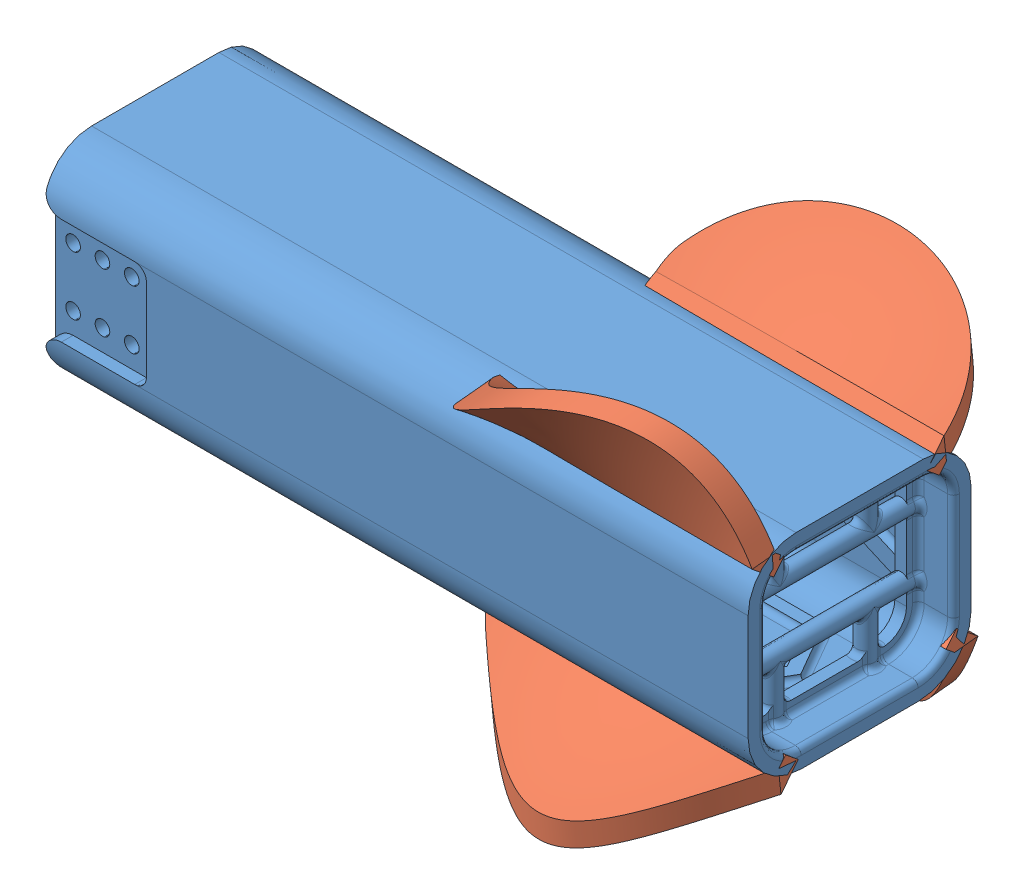
SolidWorks assembly 飞镖带尾翼, configuration 默认. Lengths in mm.
Overall size (122.83 75.54 74.98).
5 component instances, 2 part files, 12 mates.
Components (placement in the parent):
- Tropedo_Body_V1-1: Tropedo_Body_V1 [默认] at (-106.8542 4.5498 -0.0001) size (120 35.32 38.34)
- 17右上螺旋翼-1: 17右上螺旋翼 [默认] at (-6.8542 38.1319 18.8007) x (0 0.104528 -0.994522) z (1 0 0) size (23.15 26.77 62.83)
- 17右上螺旋翼-2: 17右上螺旋翼 [默认] at (-6.8542 9.1481 -20.6645) x (0 -0.104528 0.994522) z (1 0 0) size (23.15 26.77 62.83)
- 17右上螺旋翼-3: 17右上螺旋翼 [默认] at (-6.8542 2.0359 13.35) x (0 0.994522 0.104528) z (1 0 0) size (23.15 26.77 62.83)
- 17右上螺旋翼-4: 17右上螺旋翼 [默认] at (-6.8542 42.0551 -14.3247) x (0 -0.994522 -0.104528) z (1 0 0) size (23.15 26.77 62.83)
Mates (geometry in assembly coordinates):
- 重合11: coincident aligned: plane of Tropedo_Body_V1-1 through (-6.8542 13.5535 9.9594) normal (1 0 0); plane of 17右上螺旋翼-1 through (-6.8542 38.1319 18.8007) normal (1 0 0)
- 重合4: coincident aligned: plane of 17右上螺旋翼-1 through (-6.8542 38.1319 18.8007) normal (1 0 0); plane of 17右上螺旋翼-3 through (-6.8542 2.0359 13.35) normal (1 0 0)
- 重合6: coincident aligned: plane of 17右上螺旋翼-2 through (-6.8542 9.1481 -20.6645) normal (1 0 0); plane of 17右上螺旋翼-3 through (-6.8542 2.0359 13.35) normal (1 0 0)
- 重合8: coincident aligned: plane of 17右上螺旋翼-1 through (-6.8542 38.1319 18.8007) normal (1 0 0); plane of 17右上螺旋翼-4 through (-6.8542 42.0551 -14.3247) normal (1 0 0)
- 相切1: tangent: curve of Tropedo_Body_V1-1; plane of 17右上螺旋翼-3 through (-26.8542 5.9769 10.1586) normal (0 0.777146 -0.62932)
- 相切3: tangent: edge_curve of Tropedo_Body_V1-1; plane of 17右上螺旋翼-2 through (-26.8542 12.3395 -16.7236) normal (0 0.62932 0.777146)
- 相切4: tangent: edge_curve of Tropedo_Body_V1-1; plane of 17右上螺旋翼-4 through (-26.8542 38.1141 -11.1333) normal (0 -0.777146 0.62932)
- 相切5: tangent: edge_curve of Tropedo_Body_V1-1; plane of 17右上螺旋翼-1 through (-26.8542 34.9406 14.8597) normal (0 -0.62932 -0.777146)
- 平行6: parallel anti-aligned: line of Tropedo_Body_V1-1 through (-26.8542 7.2098 14.9999) axis (0 0.707107 -0.707107); line of 17右上螺旋翼-3 through (-76.8542 7.9794 12.6315) axis (0 -0.707107 0.707107)
- 平行7: parallel aligned: line of Tropedo_Body_V1-1 through (-26.8542 37.2098 14.9999) axis (0 -0.707107 -0.707107); line of 17右上螺旋翼-2 through (-76.8542 9.8666 -14.7211) axis (0 -0.707107 -0.707107)
- 平行8: parallel aligned: line of Tropedo_Body_V1-1 through (-26.8542 7.2098 14.9999) axis (0 0.707107 -0.707107); line of 17右上螺旋翼-4 through (-76.8542 36.1116 -13.6062) axis (0 0.707107 -0.707107)
- 平行9: parallel anti-aligned: line of Tropedo_Body_V1-1 through (-26.8542 37.2098 14.9999) axis (0 -0.707107 -0.707107); line of 17右上螺旋翼-1 through (-76.8542 37.4134 12.8573) axis (0 0.707107 0.707107)
